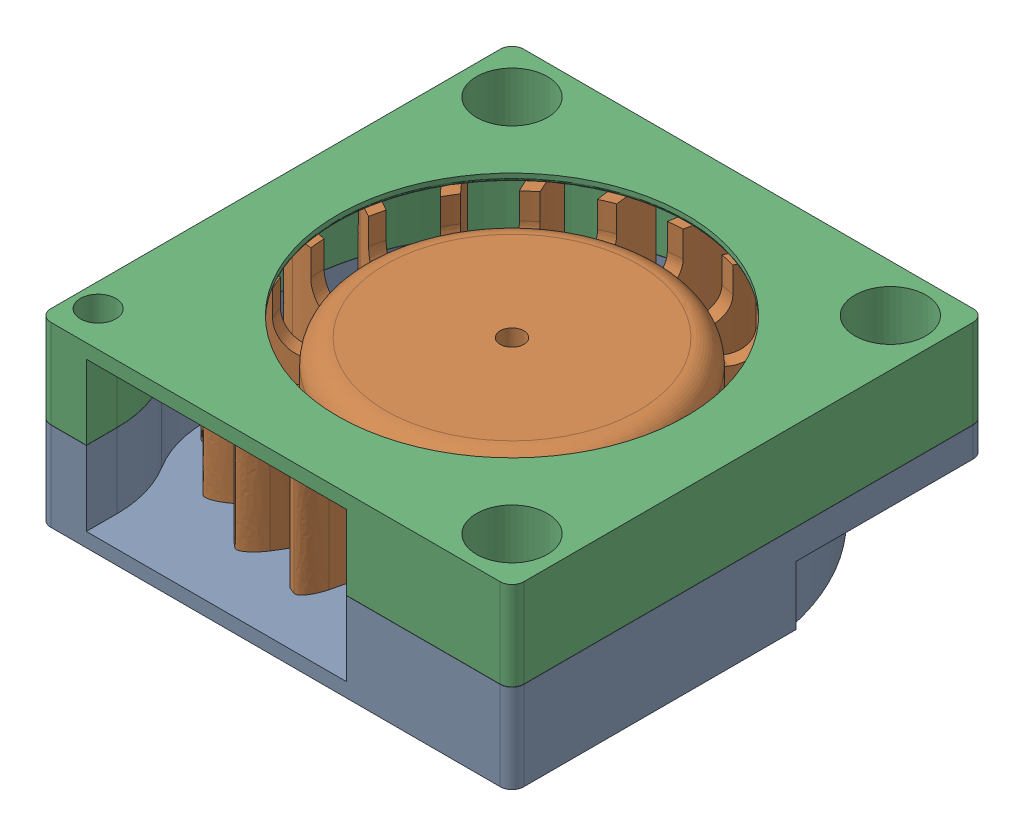
SolidWorks assembly 4015_Blower_Fan, configuration Default. Lengths in mm.
Overall size (41.36 15.02 41.36).
3 component instances, 3 part files, 4 mates.
Components (placement in the parent):
- BODY2-1: BODY2 [Default] at (-54.8836 -24.2174 40.3189) size (40 7.5 40)
- Fan-1: Fan [Default] at (-54.8836 -20.0174 40.3189) x (0.118893 0 -0.992907) z (0.992907 0 0.118893) size (37.2 9.21 37.2)
- BODY COVER-1: BODY COVER [Default] at (-54.8836 -24.1977 40.3189) size (40 7.5 40)
Mates (geometry in assembly coordinates):
- Concentric1: concentric aligned: circle of BODY2-1; cylinder of Fan-1 through (-54.8836 -20.0174 40.3189) axis (0 1 0) radius 1
- Concentric2: concentric anti-aligned: cylinder of BODY2-1 through (-70.8836 -24.2174 24.3189) axis (0 1 0) radius 1.5; cylinder of BODY COVER-1 through (-70.8836 -9.1977 24.3189) axis (0 -1 0) radius 1.5
- Coincident2: coincident aligned: plane of BODY2-1 through (-74.8836 -16.7174 60.3189) normal (-1 0 0); plane of BODY COVER-1 through (-74.8836 -16.6977 60.3189) normal (-1 0 0)
- Distance2: distance = 3 mm anti-aligned: plane of BODY2-1 through (-54.8836 -23.0174 40.3189) normal (0 1 0); plane of Fan-1 through (-54.8836 -20.0174 40.3189) normal (0 -1 0)
